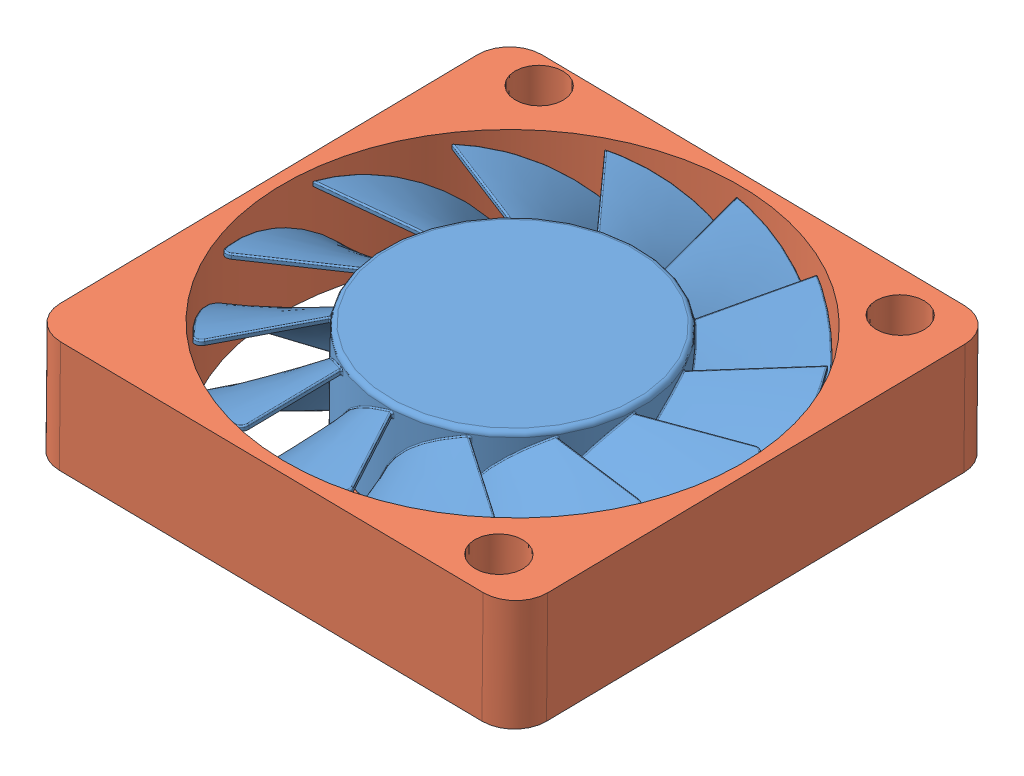
SolidWorks assembly final_assembly, configuration Default. Lengths in mm.
Overall size (31.31 8.12 31.35).
2 component instances, 2 part files, 2 mates.
Components (placement in the parent):
- RotorBlades-1: RotorBlades [Default] at (8.6141 60.8719 15.8846) x (0.997386 -0.019795 -0.069495) z (0.069287 -0.011021 0.997536) size (29.21 7.22 29.33)
- MotorHouse-3: MotorHouse [Default] at (8.5956 59.9722 15.8759) x (0.99977 -0.020451 -0.006458) z (0.006259 -0.009751 0.999933) size (30 7 30)
Mates (geometry in assembly coordinates):
- Concentric2: concentric anti-aligned: cylinder of RotorBlades-1 through (8.7252 66.2905 15.9367) axis (-0.020512 -0.999743 -0.009621) radius 0.8; cylinder of MotorHouse-3 through (8.0307 32.4385 15.611) axis (0.020512 0.999743 0.009621) radius 8
- LimitDistance1: limit distance = 0 mm: plane of RotorBlades-1 through (8.7392 66.9704 15.9433) normal (0.020512 0.999743 0.009621); plane of MotorHouse-3 through (21.8176 66.5777 28.8585) normal (0.020512 0.999743 0.009621)
